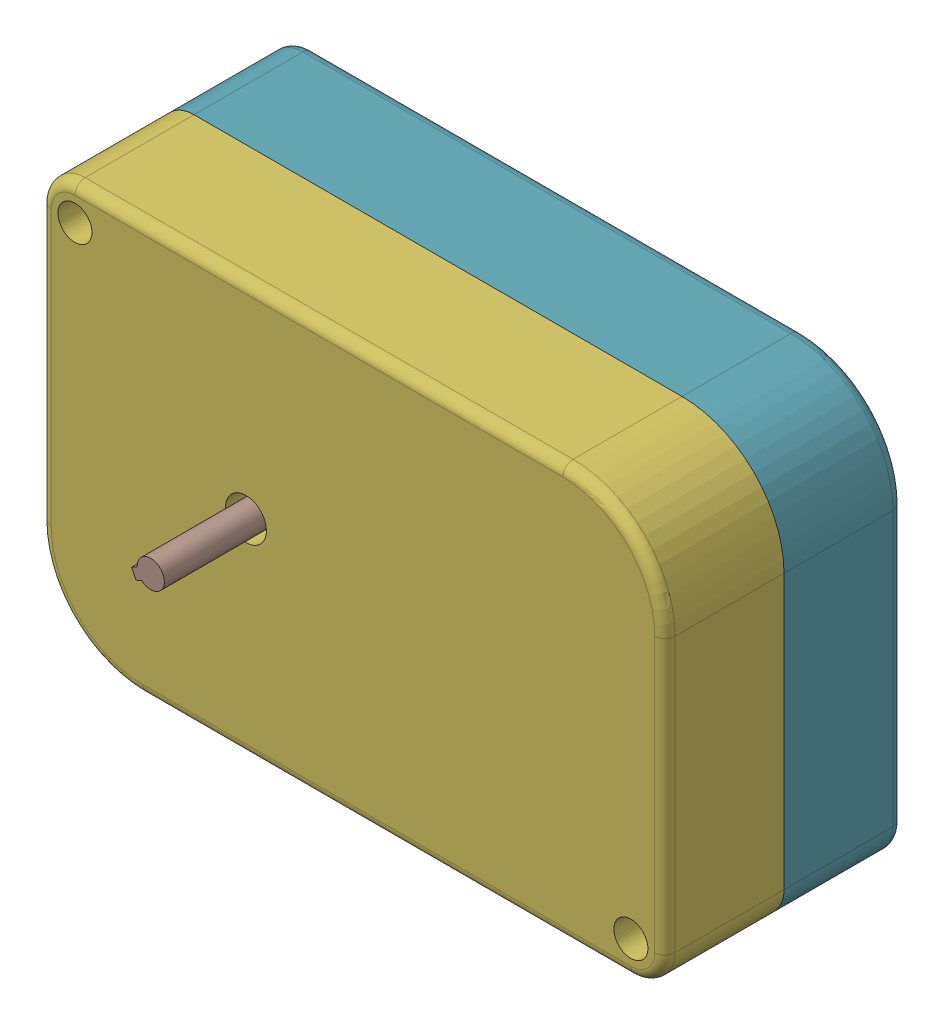
SolidWorks assembly Assem1, configuration Default. Lengths in mm.
Overall size (192.73 139.19 103).
7 component instances, 4 part files, 19 mates.
Components (placement in the parent):
- Spur gear-1: Spur gear [Default] at (0 0 -10) x (-0.834718 -0.550677 0) z (0 0 1) size (100.51 100.45 10)
- Pignon-1: Pignon [Default] at (62.84 0 -10) x (-0.983948 -0.178458 0) z (0 0 1) size (37.51 37.44 10)
- Spur gear-2: Spur gear [Default] at (62.84 0 8) x (-0.983948 -0.178458 0) z (0 0 1) size (100.51 100.45 10)
- Pignon-2: Pignon [Default] at (0 0 8) x (-0.432817 0.901482 0) z (0 0 1) size (37.51 37.44 10)
- Spur gear-4: Spur gear [Default] at (0 0 26) x (-0.432817 0.901482 0) z (0 0 1) size (100.51 100.45 10)
- Box-1: Box [Default] at (62.85 0 -12) size (183.39 120.54 75)
- Shaft-1: Shaft [Default] at (0 0 51) x (-0.432817 0.901482 0) z (0 0 1) size (8 9.5 50)
Mates (geometry in assembly coordinates):
- Concentric3: concentric aligned: cylinder of Spur gear-1 through (0 0 -10) axis (0 0 1) radius 4
- Concentric4: concentric aligned: cylinder of Pignon-1 through (62.84 0 -10) axis (0 0 1) radius 4; cylinder of Spur gear-2 through (62.84 0 8) axis (0 0 1) radius 4
- Concentric6: concentric aligned: cylinder of Pignon-1 through (62.84 0 -10) axis (0 0 1) radius 4
- Coincident4: coincident aligned: plane of Pignon-1 through (74.7421 -18.5937 0) normal (0 0 1)
- Parallel1: parallel aligned: plane of Pignon-1 through (65.5198 -1.1483 -10) normal (-0.81065 -0.585531 0); plane of Spur gear-2 through (64.056 0.8783 8) normal (-0.81065 -0.585531 0)
- Distance1: distance = 8 mm anti-aligned: plane of Pignon-1 through (65.5547 -21.9093 0) normal (0 0 1); plane of Spur gear-2 through (62.84 0 8) normal (0 0 -1)
- GearMate3: gear = 1 : 3 mm: cylinder of Spur gear-1 through (0 0 -10) axis (0 0 1) radius 4; cylinder of Pignon-1 through (62.84 0 -10) axis (0 0 1) radius 4
- GearMate4: gear = 3 : 1 mm: cylinder of Pignon-2 through (0 0 8) axis (0 0 1) radius 4; cylinder of Spur gear-2 through (62.84 0 8) axis (0 0 1) radius 4
- Concentric7: concentric aligned: cylinder of Pignon-2 through (0 0 8) axis (0 0 1) radius 4
- Coincident9: coincident anti-aligned: plane of Pignon-2 through (-12.8978 17.9174 8) normal (0 0 -1)
- Concentric8: concentric aligned: cylinder of Pignon-2 through (0 0 8) axis (0 0 1) radius 4; cylinder of Spur gear-4 through (0 0 26) axis (0 0 1) radius 4
- Parallel2: parallel aligned: plane of Pignon-2 through (-0.4058 2.8871 8) normal (-0.777532 -0.628843 0); plane of Spur gear-4 through (1.1663 0.9433 26) normal (-0.777532 -0.628843 0)
- Distance2: distance = 8 mm anti-aligned: plane of Spur gear-4 through (0 0 26) normal (0 0 -1); plane of Pignon-2 through (-20.4066 -8.4234 18) normal (0 0 1)
- Distance3: distance = 2 mm anti-aligned: plane of Spur gear-1 through (0 0 -10) normal (0 0 -1); plane of Box-1 through (62.85 0 -12) normal (0 0 1)
- Concentric10: concentric anti-aligned: cylinder of Spur gear-1 through (0 0 -10) axis (0 0 1) radius 4; cylinder of Box-1 through (0 0 3) axis (0 0 -1) radius 53.272
- Parallel9: parallel aligned: plane of Box-1 through (62.85 -53.272 13) normal (0 1 0)
- Concentric21: concentric anti-aligned: cylinder of Spur gear-4 through (0 0 26) axis (0 0 1) radius 4; cylinder of Shaft-1 through (0 0 76) axis (0 0 -1) radius 4
- Parallel10: parallel anti-aligned: plane of Spur gear-4 through (-1.1663 -0.9433 26) normal (0.777532 0.628843 0); plane of Shaft-1 through (-1.1663 -0.9433 76) normal (-0.777532 -0.628843 0)
- Coincident15: coincident anti-aligned: circle of Spur gear-4; plane of Shaft-1 through (0 0 26) normal (0 0 -1)
